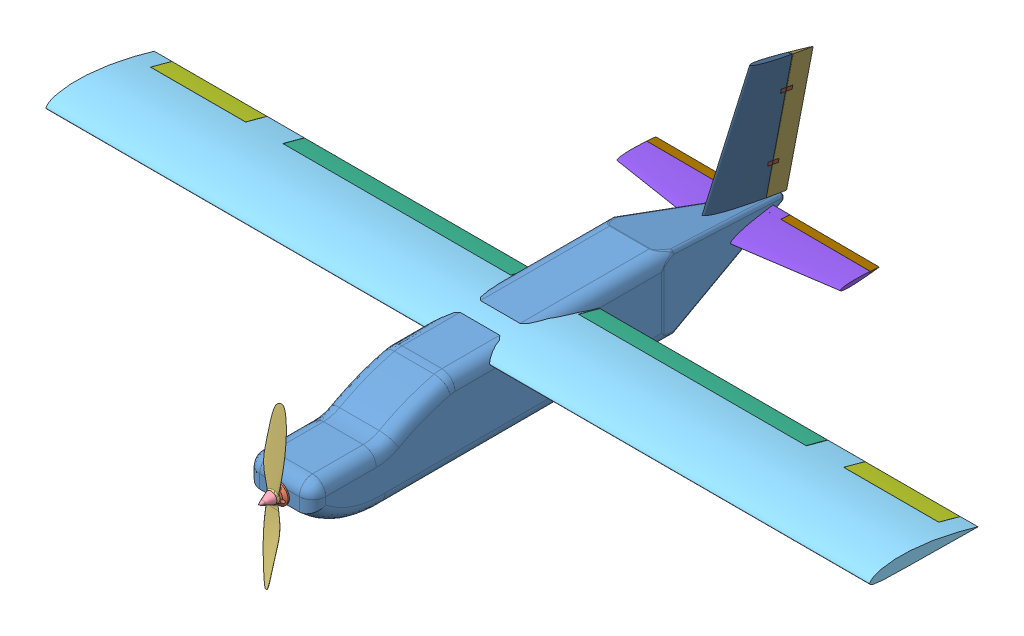
SolidWorks assembly UAV, configuration Default. Lengths in mm.
Overall size (1246.6 341.99 839.85).
49 component instances, 26 part files, 19 mates.
Components (placement in the parent):
- Fuselage-1: Fuselage [Default] at (363.6622 358.1364 725.4045) size (100 127.54 760.96)
- Propulsion system assembly-1: Propulsion system assembly [Default] at (275.7172 409.4872 918.5958) x (0.37277 0.927924 0) z (0.927924 -0.37277 0) size (257.04 52.9 102.49)
  - Electric motor-1: Electric motor [Default] at (12.8913 -4.1913 35.7137) size (40 40.5 40)
  - Propeller - 30deg twist-1: Propeller - 30deg twist [Default] at (9.5179 26.7661 36.8819) x (0.267188 0.098233 0.958624) z (-0.963211 -0.002607 0.268734) size (34.11 7.29 257.18)
  - Propeller spinner-1: Propeller spinner [Default] at (12.8913 24.3087 35.7137) size (17 24.4 17)
- Main gear assembly-1: Main gear assembly [Default] at (243.3007 39.7715 302.2916) size (390.85 251.73 81.62) (hidden)
  - Main Gear-1: Main Gear [Default] at (56.8356 250.9419 269.2629) size (346.85 220.92 20)
  - Bolt-1: Bolt [Default] at (265.5864 107.4488 278.7975) x (0 0.8029 0.596114) z (-1 0 0) size (7.5 7.5 26.03)
  - Nut-1: Nut [Default] at (262.5864 107.4488 278.7975) x (1 0 0) z (0 0.308408 0.951254) size (2 7.5 7.5)
  - Tire-1: Tire [Default] at (244.5864 107.4488 278.7975) x (0 -0.633726 -0.773558) z (0 -0.773558 0.633726) size (58 17 58)
  - Washer-1: Washer [Default] at (243.5864 107.4488 278.7975) size (1 15 15)
  - Washer-2: Washer [Default] at (261.5864 107.4488 278.7975) x (1 0 0) z (0 -0.986827 0.16178) size (1 15 15)
  - Bolt-2: Bolt [Default] at (-125.2675 107.4488 278.7975) x (0 0 -1) z (1 0 0) size (7.5 7.5 26.03)
  - Nut-2: Nut [Default] at (-124.2675 107.4488 278.7975) size (2 7.5 7.5)
  - Tire-2: Tire [Default] at (-121.2675 107.4488 278.7975) x (0 -0.618786 0.78556) z (0 0.78556 0.618786) size (58 17 58)
  - Washer-3: Washer [Default] at (-104.2675 107.4488 278.7975) size (1 15 15)
  - Washer-4: Washer [Default] at (-122.2675 107.4488 278.7975) size (1 15 15)
- Nose gear-1: Nose gear [Default] at (343.8146 288.3053 836.9422) size (62 252.42 122.59) (hidden)
  - Vertical component-1: Vertical component [Default] at (-31.1524 -100.1689 34.5181) size (2 175 20)
  - Slant component-1: Slant component [Default] at (-29.1524 -158.5949 -58.2131) x (1 0 0) z (0 -0.839643 0.543138) size (2 110 20)
  - Fillet-1: Fillet [Default] at (-31.1524 -93.1689 24.5181) x (0 0.66508 -0.746772) z (0 0.746772 0.66508) size (6 6 6)
  - Fuselage attachment-1: Fuselage attachment [Default] at (-29.1524 44.8311 34.5181) size (30 30 20)
  - Fuselage attachment-2: Fuselage attachment [Default] at (-31.1524 44.8311 14.5181) x (-1 0 0) z (0 0 -1) size (30 30 20)
  - Fillet-2: Fillet [Default] at (-28.1524 64.8311 24.5181) x (0 -0.871668 0.490096) z (0 0.490096 0.871668) size (6 6 6)
  - Fillet-3: Fillet [Default] at (-28.1524 54.8311 24.5181) x (0 -0.117224 -0.993105) z (0 -0.993105 0.117224) size (6 6 6)
  - End of travel - EOT rod-1: End of travel - EOT rod [Default] at (-27.1524 -127.9074 -23.8031) x (1 0 0) z (0 -0.404439 0.914565) size (2 120 10)
  - Fillet-4: Fillet [Default] at (-29.1524 -121.3124 -26.3538) x (0 0.796971 -0.604018) z (0 0.604018 0.796971) size (6 6 6)
  - Rivet 2-2: Rivet 2 [Default] at (-25.1524 -20.7102 18.1345) x (0 0.920891 0.38982) z (0 0.38982 -0.920891) size (6 10 6)
  - Part8^Nose gear-1: Part8^Nose gear [Default] at origin size (15.37 95.27 53.12) (virtual)
  - Bolt-1: Bolt [Default] at (-50.1524 -144.767 -55.248) x (0 0 -1) z (1 0 0) size (7.5 7.5 26.03)
  - Nut-1: Nut [Default] at (-49.1524 -144.767 -55.248) x (1 0 0) z (0 -0.314496 -0.949259) size (2 7.5 7.5)
  - Tire washer-1: Tire washer [Default] at (-27.1524 -144.767 -55.248) size (1 15 15)
  - Tire-1: Tire [Default] at (-30.1524 -144.767 -55.248) x (0 0.989877 0.141929) z (0 -0.141929 0.989877) size (58 17 58)
  - Tire washer-2: Tire washer [Default] at (-30.1524 -144.767 -55.248) size (1 15 15)
  - E.O.T. washer-1: E.O.T. washer [Default] at (-32.1524 -20.7102 18.1345) x (0 0 -1) z (1 0 0) size (10 10 1)
- Wing-6: Wing [Default] at (290.5889 454.2138 526.7116) x (0 -0.04885 -0.998806) z (1 0 0) size (164.12 20 1246.6)
  - Wing_clark y-1: Wing_clark y [Default] at (-139.163 5.3912 -600.2268) size (164.12 20 1246.6)
  - Flap_clark y-1: Flap_clark y [Default] at (-139.2386 5.304 74.5732) x (1 0.000694 0) z (0 0 1) size (37.04 8.48 344.25)
  - Flap_clark y-2: Flap_clark y [Default] at (-139.2407 5.3972 -372.6768) size (37.04 8.48 344.25)
  - Aileron_clark y-1: Aileron_clark y [Default] at (-139.2427 5.4942 475.6732) x (1 -0.000707 0) z (0 0 1) size (35.18 8.49 143.81)
  - Aileron_clark y-2: Aileron_clark y [Default] at (-139.2407 5.3972 -573.3268) size (35.18 8.49 143.81)
- Horizontal tail-2: Horizontal tail [Default] at (286.9597 440.6773 215.3864) x (-0.000005 0.023208 -0.999731) z (0.999987 -0.005108 -0.000124) size (85.11 8.6 338.26)
  - Horizontal tail-1: Horizontal tail [Default] at (-66.2781 -20.6872 26.8582) size (85.11 8.6 338.25)
  - Elevator-2: Elevator [Default] at (-66.35 -20.0514 26.8582) x (0.999962 -0.008739 0) z (0 0 1) size (14.77 3.27 338.26)
- Vertical tail-1: Vertical tail [Default] at (217.5948 675.3276 221.9261) x (-0.000958 -0.232932 -0.972492) z (0 -0.972493 0.232932) size (132.07 10.81 173.2)
  - Vertical tail - rudder cut-1: Vertical tail - rudder cut [Default] at (-19.4442 96.0489 234.5051) size (131.87 10.81 173.19)
  - Vertical tail - Rudder hinge-1: Vertical tail - Rudder hinge [Default] at (-19.4442 96.0645 272.3617) size (23.51 6.78 5.15)
  - Vertical tail - Rudder hinge-2: Vertical tail - Rudder hinge [Default] at (-19.4442 96.0645 184.3617) size (23.51 6.78 5.15)
  - Rudder-1: Rudder [Default] at (-19.4442 95.9836 234.5051) x (1 0.000643 0) z (0 0 1) size (36.62 5.96 173.2)
Mates (geometry in assembly coordinates):
- Concentric1: concentric anti-aligned: cylinder of Fuselage-1 through (313.6622 408.1364 915.4045) axis (0 0 1) radius 15; cylinder of Propulsion system assembly-1/Electric motor-1 through (313.6622 408.1364 914.4045) axis (0 0 -1) radius 15
- Coincident1: coincident anti-aligned: plane of Fuselage-1 through (313.6622 408.1364 915.4045) normal (0 0 1); plane of Propulsion system assembly-1/Electric motor-1 through (314.2531 409.6072 915.4045) normal (0 0 -1)
- Coincident2: coincident anti-aligned: plane of Fuselage-1 through (263.6622 358.1364 725.4045) normal (0 -1 0); plane of Main gear assembly-1/Main Gear-1 through (354.4727 358.1364 591.5545) normal (0 1 0)
- Distance1: distance = 233.85 mm: line of Main gear assembly-1/Main Gear-1 through (354.4727 358.1364 591.5545) axis (-1 0 0); line of Fuselage-1 through (283.6622 358.1364 825.4045) axis (1 0 0)
- Parallel1: parallel anti-aligned: line of Fuselage-1 through (283.6622 358.1364 825.4045) axis (1 0 0); line of Main gear assembly-1/Main Gear-1 through (354.4727 358.1364 591.5545) axis (-1 0 0)
- Distance2: distance = 10 mm: line of Main gear assembly-1/Main Gear-1 through (353.4602 356.1364 591.5545) axis (0 0 -1); line of Fuselage-1 through (343.6622 358.1364 405.995) axis (0 0 1)
- Distance3: distance = 260 mm: line of Main gear assembly-1/Main Gear-1 through (273.4602 356.1364 591.5545) axis (1 0 0); line of Nose gear-1/Vertical component-1 through (314.6622 363.1364 851.4603) axis (-1 0 0)
- Perpendicular1: perpendicular: line of Fuselage-1 through (363.6622 378.1364 825.6859) axis (0 0 -1); line of Nose gear-1/Vertical component-1 through (314.6622 188.1364 851.4603) axis (0 1 0)
- Distance5: distance = 75 mm aligned: plane of Nose gear-1/Vertical component-1 through (314.6622 363.1364 871.4603) normal (0 1 0); plane of Fuselage-1 through (263.6622 438.1364 825.4045) normal (0 1 0)
- Distance10: distance = 29 mm: line of Fuselage-1 through (283.6622 438.1364 838.8372) axis (0 0 1); plane of Nose gear-1/Vertical component-1 through (312.6622 188.1364 871.4603) normal (-1 0 0)
- Parallel34: parallel aligned: line of Fuselage-1 through (343.6622 478.1364 405.995) axis (-1 0 0); line of Wing-6/Wing_clark y-1 through (364.6621 458.4834 501.6361) axis (-1 0 0)
- Distance21: distance = 573.3 mm: line of Wing-6/Wing_clark y-1 through (936.9621 466.3966 665.4451) axis (0 -0.04885 -0.998806); line of Fuselage-1 through (363.6622 458.1364 505.2525) axis (0 0.04885 0.998806)
- Distance23: distance = 219 mm: line of Wing-6/Wing_clark y-1 through (364.6621 458.4834 501.6361) axis (-1 0 0); line of Fuselage-1 through (283.6622 478.1364 719.7525) axis (1 0 0)
- Distance25: distance = 97.6394 mm: line of Wing-6/Wing_clark y-1 through (364.6621 458.4834 501.6361) axis (-1 0 0); line of Fuselage-1 through (343.6622 478.1364 405.995) axis (-1 0 0)
- Distance27: distance = 673.3003 mm: line of Fuselage-1 through (363.6622 458.1364 505.2525) axis (0 0.04885 0.998806); line of Wing-6/Wing_clark y-1 through (-309.6379 466.3966 665.4451) axis (0 -0.04885 -0.998806)
- Lock2: lock: unknown of Fuselage-1; unknown of Horizontal tail-2/Horizontal tail-1
- Coincident26: coincident: line of Fuselage-1 through (313.6622 423.9758 179.284) axis (0 0.232932 0.972493); line of Vertical tail-1/Vertical tail - rudder cut-1 through (313.6622 451.7808 295.3698) axis (0 -0.232932 -0.972493)
- Coincident27: coincident: plane of Fuselage-1 through (263.6622 418.1364 154.9045) normal (0 0.972493 -0.232932); plane of Vertical tail-1/Vertical tail - rudder cut-1 through (313.6622 451.7808 295.3698) normal (0 -0.972493 0.232932)
- Lock3: lock: unknown of Fuselage-1; unknown of Vertical tail-1/Vertical tail - rudder cut-1
